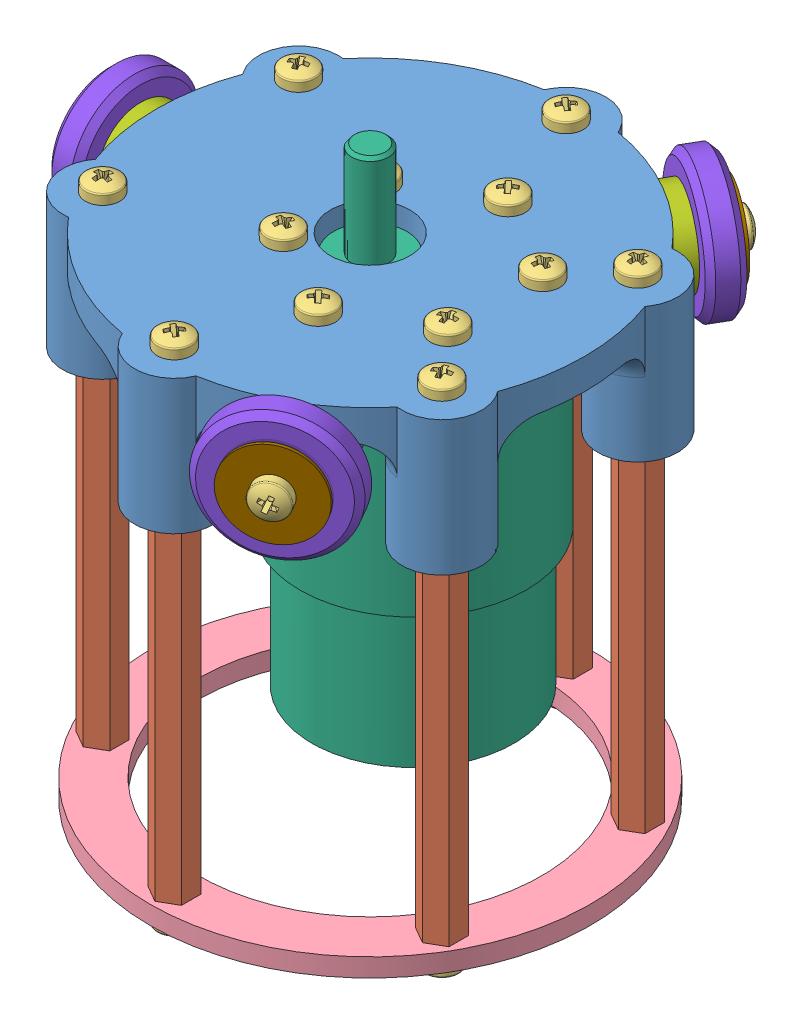
SolidWorks assembly Base, configuration По умолчанию. Lengths in mm.
Overall size (98.35 95.05 98.35).
40 component instances, 9 part files, 41 mates.
Components (placement in the parent):
- base-1: base [По умолчанию] at (1.2511 4.8347 -0.0783) size (70.02 22 77)
- стойка-1: стойка [По умолчанию] at (-26.4618 -67.1653 15.9217) x (-0.026451 0 0.99965) z (-0.99965 0 -0.026451) size (6.35 60 5.58)
- стойка-2: стойка [По умолчанию] at (28.964 -67.1653 15.9217) x (-0.026451 0 0.99965) z (-0.99965 0 -0.026451) size (6.35 60 5.58)
- стойка-3: стойка [По умолчанию] at (1.2511 -67.1653 31.9217) x (-0.026451 0 0.99965) z (-0.99965 0 -0.026451) size (6.35 60 5.58)
- стойка-4: стойка [По умолчанию] at (28.964 -67.1653 -16.0784) x (-0.878948 0 0.476918) z (-0.476918 0 -0.878948) size (6.35 60 5.58)
- стойка-5: стойка [По умолчанию] at (1.2511 -67.1653 -32.0784) x (-0.878948 0 0.476918) z (-0.476918 0 -0.878948) size (6.35 60 5.58)
- стойка-6: стойка [По умолчанию] at (-26.4618 -67.1653 -16.0784) x (-0.878948 0 0.476918) z (-0.476918 0 -0.878948) size (6.35 60 5.58)
- pan head cross recess screw_iso-5: pan head cross recess screw_iso [ISO 7045 - M3 x 16 - Z - 16N] at (28.964 12.2347 -16.0784) x (0 -1 0) z (0.120433 0 -0.992721) size (18.35 5.6 5.6)
- pan head cross recess screw_iso-6: pan head cross recess screw_iso [ISO 7045 - M3 x 16 - Z - 16N] at (1.2511 -72.5653 -32.0784) x (0 1 0) z (-0.866025 0 -0.5) size (18.35 5.6 5.6)
- pan head cross recess screw_iso-7: pan head cross recess screw_iso [ISO 7045 - M3 x 16 - Z - 16N] at (1.2511 12.2347 -32.0784) x (0 -1 0) z (-0.799506 0 -0.600659) size (18.35 5.6 5.6)
- pan head cross recess screw_iso-8: pan head cross recess screw_iso [ISO 7045 - M3 x 16 - Z - 16N] at (-26.4618 12.2347 -16.0784) x (0 -1 0) z (-0.919938 0 0.392063) size (18.35 5.6 5.6)
- pan head cross recess screw_iso-9: pan head cross recess screw_iso [ISO 7045 - M3 x 16 - Z - 16N] at (-26.4618 12.2347 15.9217) x (0 -1 0) z (-0.120433 0 0.992721) size (18.35 5.6 5.6)
- pan head cross recess screw_iso-10: pan head cross recess screw_iso [ISO 7045 - M3 x 16 - Z - 16N] at (1.2511 12.2347 31.9217) x (0 -1 0) z (0.799506 0 0.600659) size (18.35 5.6 5.6)
- pan head cross recess screw_iso-11: pan head cross recess screw_iso [ISO 7045 - M3 x 16 - Z - 16N] at (28.964 12.2347 15.9217) x (0 -1 0) z (0.919938 0 -0.392063) size (18.35 5.6 5.6)
- bottomRing-1: bottomRing [По умолчанию] at (1.2511 -70.1653 -0.0784) x (0.5 0 -0.866025) z (0.866025 0 0.5) size (72 3 72)
- pan head cross recess screw_iso-12: pan head cross recess screw_iso [ISO 7045 - M3 x 16 - Z - 16N] at (-26.4617 -72.5653 -16.0784) x (0 1 0) z (-0.866025 0 0.5) size (18.35 5.6 5.6)
- pan head cross recess screw_iso-13: pan head cross recess screw_iso [ISO 7045 - M3 x 16 - Z - 16N] at (-26.4617 -72.5653 15.9216) x (0 1 0) z (0 0 1) size (18.35 5.6 5.6)
- pan head cross recess screw_iso-14: pan head cross recess screw_iso [ISO 7045 - M3 x 16 - Z - 16N] at (1.2511 -72.5653 31.9216) x (0 1 0) z (0.866025 0 0.5) size (18.35 5.6 5.6)
- pan head cross recess screw_iso-15: pan head cross recess screw_iso [ISO 7045 - M3 x 16 - Z - 16N] at (28.9639 -72.5653 15.9216) x (0 1 0) z (0.866025 0 -0.5) size (18.35 5.6 5.6)
- pan head cross recess screw_iso-16: pan head cross recess screw_iso [ISO 7045 - M3 x 16 - Z - 16N] at (28.9639 -72.5653 -16.0784) x (0 1 0) z (0 0 -1) size (18.35 5.6 5.6)
- gasket-1: gasket [По умолчанию] at (8.2511 1.0347 -0.0783) x (-1 0 0) z (0 0 -1) size (37 3.8 37)
- двигатель1-1: двигатель1 [По умолчанию] at (8.2511 -55.6653 -0.0783) size (37 78.2 37)
- pan head cross recess screw_iso-18: pan head cross recess screw_iso [ISO 7045 - M3 x 16 - Z - 16N] at (8.2511 12.2347 15.4217) x (0 -1 0) z (-0.744188 0 0.66797) size (18.35 5.6 5.6)
- pan head cross recess screw_iso-20: pan head cross recess screw_iso [ISO 7045 - M3 x 16 - Z - 16N] at (-5.1723 12.2347 7.6717) x (0 -1 0) z (-0.950573 0 -0.310501) size (18.35 5.6 5.6)
- pan head cross recess screw_iso-21: pan head cross recess screw_iso [ISO 7045 - M3 x 16 - Z - 16N] at (-5.1723 12.2347 -7.8283) x (0 -1 0) z (-0.206385 0 -0.978471) size (18.35 5.6 5.6)
- pan head cross recess screw_iso-22: pan head cross recess screw_iso [ISO 7045 - M3 x 16 - Z - 16N] at (8.2511 12.2347 -15.5783) x (0 -1 0) z (0.744188 0 -0.66797) size (18.35 5.6 5.6)
- pan head cross recess screw_iso-23: pan head cross recess screw_iso [ISO 7045 - M3 x 16 - Z - 16N] at (21.6745 12.2347 -7.8283) x (0 -1 0) z (0.950573 0 0.310501) size (18.35 5.6 5.6)
- pan head cross recess screw_iso-24: pan head cross recess screw_iso [ISO 7045 - M3 x 16 - Z - 16N] at (21.6745 12.2347 7.6717) x (0 -1 0) z (0.206385 0 0.978471) size (18.35 5.6 5.6)
- КреплениеПодшипника-1: КреплениеПодшипника [По умолчанию] at (-33.7642 -4.4235 -0.8422) x (0 0.10912 -0.994029) z (1 0 0) size (14 14 7.61)
- подшипник-1: подшипник [По умолчанию] at (-41.2642 2.5347 -0.0783) x (0 -0.869908 0.493213) z (0 0.493213 0.869908) size (21 5 21)
- Заглушка-1: Заглушка [По умолчанию] at (-42.2642 2.5347 -0.0783) x (0 -0.189221 -0.981934) z (0 -0.981934 0.189221) size (14 2 14)
- pan head cross recess screw_iso-25: pan head cross recess screw_iso [ISO 7045 - M3 x 12 - Z - 12N] at (-44.6642 2.5347 -0.0783) x (1 0 0) z (0 0.929064 0.369918) size (14.35 5.6 5.6)
- pan head cross recess screw_iso-26: pan head cross recess screw_iso [ISO 7045 - M3 x 12 - Z - 12N] at (24.2088 2.5347 39.6855) x (-0.5 0 -0.866025) z (0.320359 0.929064 -0.184959) size (14.35 5.6 5.6)
- pan head cross recess screw_iso-27: pan head cross recess screw_iso [ISO 7045 - M3 x 12 - Z - 12N] at (24.2088 2.5347 -39.8422) x (-0.5 0 0.866025) z (-0.320359 0.929064 -0.184959) size (14.35 5.6 5.6)
- Заглушка-2: Заглушка [По умолчанию] at (23.0088 2.5347 37.607) x (-0.85038 -0.189221 0.490967) z (0.16387 -0.981934 -0.094611) size (14 2 14)
- Заглушка-3: Заглушка [По умолчанию] at (23.0088 2.5347 -37.7637) x (0.85038 -0.189221 0.490967) z (-0.16387 -0.981934 -0.094611) size (14 2 14)
- подшипник-2: подшипник [По умолчанию] at (22.5088 2.5347 36.741) x (0.427135 -0.869908 -0.246607) z (0.753363 0.493213 -0.434954) size (21 5 21)
- подшипник-3: подшипник [По умолчанию] at (22.5088 2.5347 -36.8977) x (-0.427135 -0.869908 -0.246607) z (-0.753363 0.493213 -0.434954) size (21 5 21)
- КреплениеПодшипника-2: КреплениеПодшипника [По умолчанию] at (18.0973 -4.4235 30.6277) x (-0.860854 0.10912 0.497014) z (-0.5 0 -0.866025) size (14 14 7.61)
- КреплениеПодшипника-3: КреплениеПодшипника [По умолчанию] at (19.4203 -4.4235 -30.0206) x (0.860854 0.10912 0.497014) z (-0.5 0 0.866025) size (14 14 7.61)
Mates (geometry in assembly coordinates):
- Концентричный1: concentric aligned: circle of base-1; circle of стойка-1
- Совпадение1: coincident anti-aligned: plane of base-1 through (1.2511 -7.1653 -0.0783) normal (0 -1 0); plane of стойка-1 through (-26.4618 -7.1653 15.9217) normal (0 1 0)
- Параллельность1: parallel anti-aligned: plane of base-1 through (-23.6618 -7.1653 17.5383) normal (-0.5 0 -0.866025); plane of стойка-1 through (-26.4618 -7.1653 19.0971) normal (0.5 0 0.866025)
- Концентричный2: concentric aligned: circle of base-1; circle of стойка-2
- Параллельность2: parallel aligned: plane of base-1 through (26.164 -7.1653 14.3051) normal (0.5 0 0.866025); plane of стойка-2 through (28.964 -7.1653 19.0971) normal (0.5 0 0.866025)
- Совпадение2: coincident anti-aligned: plane of base-1 through (1.2511 -7.1653 -0.0783) normal (0 -1 0); plane of стойка-2 through (28.964 -7.1653 15.9217) normal (0 1 0)
- Концентричный3: concentric aligned: circle of base-1; circle of стойка-3
- Параллельность3: parallel aligned: plane of base-1 through (1.2511 -7.1653 28.6886) normal (-0.5 0 0.866025); plane of стойка-3 through (-1.4989 -7.1653 33.5095) normal (-0.5 0 0.866025)
- Совпадение3: coincident anti-aligned: plane of base-1 through (1.2511 -7.1653 -0.0783) normal (0 -1 0); plane of стойка-3 through (1.2511 -7.1653 31.9217) normal (0 1 0)
- Концентричный4: concentric aligned: circle of base-1; circle of стойка-4
- Параллельность4: parallel aligned: plane of base-1 through (26.164 -7.1653 -14.4618) normal (1 0 0); plane of стойка-4 through (31.714 -7.1653 -14.4907) normal (1 0 0)
- Совпадение4: coincident anti-aligned: plane of base-1 through (1.2511 -7.1653 -0.0783) normal (0 -1 0); plane of стойка-4 through (28.964 -7.1653 -16.0784) normal (0 1 0)
- Концентричный5: concentric aligned: circle of base-1; circle of стойка-5
- Параллельность5: parallel aligned: plane of base-1 through (-1.5489 -7.1653 -30.4619) normal (1 0 0); plane of стойка-5 through (4.0011 -7.1653 -30.4907) normal (1 0 0)
- Совпадение5: coincident anti-aligned: plane of base-1 through (1.2511 -7.1653 -0.0783) normal (0 -1 0); plane of стойка-5 through (1.2511 -7.1653 -32.0784) normal (0 1 0)
- Концентричный6: concentric aligned: circle of base-1; circle of стойка-6
- Параллельность6: parallel aligned: plane of base-1 through (-29.2618 -7.1653 -14.4618) normal (1 0 0); plane of стойка-6 through (-23.7118 -7.1653 -14.4907) normal (1 0 0)
- Совпадение6: coincident anti-aligned: plane of base-1 through (1.2511 -7.1653 -0.0783) normal (0 -1 0); plane of стойка-6 through (-26.4618 -7.1653 -16.0784) normal (0 1 0)
- Концентричный7: concentric aligned: circle of base-1; circle of pan head cross recess screw_iso-5
- Совпадение9: coincident anti-aligned: plane of base-1 through (-12.6053 9.8347 7.9217) normal (0 1 0); plane of pan head cross recess screw_iso-5 through (27.4749 9.8347 -16.259) normal (0 -1 0)
- Концентричный8: concentric anti-aligned: circle of стойка-6; circle of bottomRing-1
- Концентричный10: concentric anti-aligned: circle of стойка-5; circle of bottomRing-1
- Совпадение10: coincident anti-aligned: plane of стойка-6 through (-26.4618 -67.1653 -16.0784) normal (0 -1 0); plane of bottomRing-1 through (1.2511 -67.1653 -0.0784) normal (0 1 0)
- Концентричный11: concentric anti-aligned: circle of pan head cross recess screw_iso-6; circle of bottomRing-1
- Совпадение11: coincident anti-aligned: plane of pan head cross recess screw_iso-6 through (2.0011 -70.1653 -33.3775) normal (0 1 0); plane of bottomRing-1 through (1.2511 -70.1653 -0.0784) normal (0 -1 0)
- Концентричный12: concentric aligned: circle of base-1; circle of gasket-1
- Концентричный13: concentric aligned: circle of base-1; circle of gasket-1
- Совпадение12: coincident anti-aligned: plane of base-1 through (-12.6053 4.8347 7.9217) normal (0 -1 0); plane of gasket-1 through (8.2511 4.8347 -0.0783) normal (0 1 0)
- Концентричный14: concentric aligned: circle of base-1; circle of двигатель1-1
- Концентричный15: concentric aligned: circle of base-1; circle of двигатель1-1
- Совпадение15: coincident anti-aligned: plane of gasket-1 through (8.2511 1.0347 -0.0783) normal (0 -1 0); plane of двигатель1-1 through (8.2511 1.0347 -0.0783) normal (0 1 0)
- Концентричный16: concentric: circle of base-1; circle of pan head cross recess screw_iso-18
- Совпадение16: coincident: plane of base-1 through (-12.6053 9.8347 7.9217) normal (0 1 0); plane of pan head cross recess screw_iso-18 through (9.2531 9.8347 16.5379) normal (0 -1 0)
- Концентричный18: concentric anti-aligned: circle of base-1; circle of КреплениеПодшипника-1
- Касательность2: tangent aligned: cylinder of base-1 through (1.2511 -3.1653 -0.0783) axis (0 1 0) radius 35.0153; cylinder of КреплениеПодшипника-1 through (1.2358 9.4929 0.6855) axis (0 -0.994029 -0.10912) radius 35
- Концентричный19: concentric anti-aligned: circle of КреплениеПодшипника-1; circle of подшипник-1
- Совпадение18: coincident anti-aligned: plane of КреплениеПодшипника-1 through (-36.2642 10.2567 -6.2727) normal (-1 0 0); plane of подшипник-1 through (-36.2642 2.5347 -0.0783) normal (1 0 0)
- Концентричный20: concentric aligned: circle of КреплениеПодшипника-1; circle of Заглушка-1
- Совпадение19: coincident anti-aligned: plane of КреплениеПодшипника-1 through (-40.2642 2.5347 -0.0783) normal (-1 0 0); plane of Заглушка-1 through (-40.2642 2.5347 -0.0783) normal (1 0 0)
- Концентричный21: concentric aligned: circle of Заглушка-1; circle of pan head cross recess screw_iso-25
- Совпадение20: coincident anti-aligned: plane of Заглушка-1 through (-42.2642 2.5347 -0.0783) normal (-1 0 0); plane of pan head cross recess screw_iso-25 through (-42.2642 3.0896 -1.4719) normal (1 0 0)
